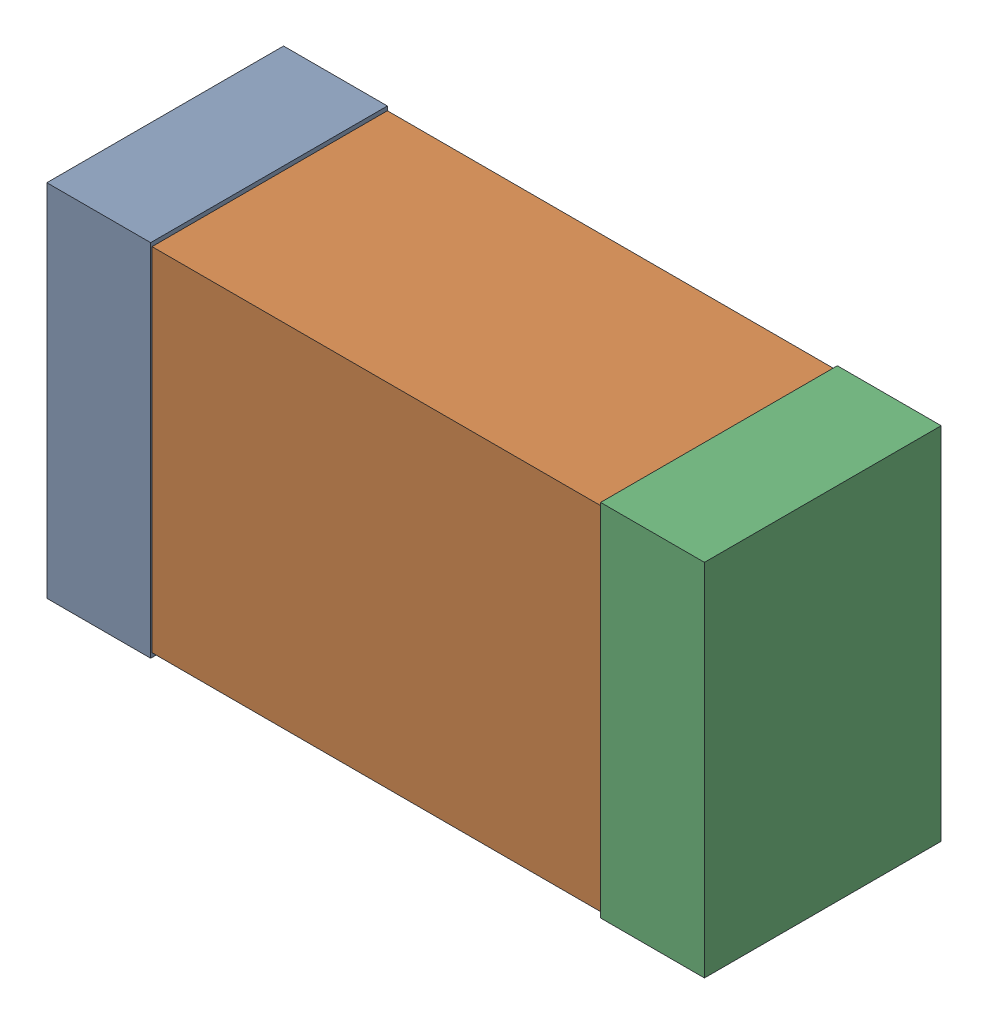
SolidWorks assembly C9_Motor_5Kanaloa_v2.0.0_Motor, configuration Default. Lengths in mm.
Overall size (2.38 1.3 0.85).
6 component instances, 2 part files, 0 mates.
Components (placement in the parent):
- 352877648-1: 352877648 [Default] at (119.294 78.232 0) size (0.38 1.3 0.85)
  - Extruded_14-1: Extruded_14 [Default] at origin size (0.38 1.3 0.85)
- 352877392-1: 352877392 [Default] at (120.294 78.232 0) size (2.2 1.27 0.85)
  - Extruded_15-1: Extruded_15 [Default] at origin size (2.2 1.27 0.85)
- 352877648-2: 352877648 [Default] at (121.294 78.232 0) size (0.38 1.3 0.85)
  - Extruded_14-1: Extruded_14 [Default] at origin size (0.38 1.3 0.85)
